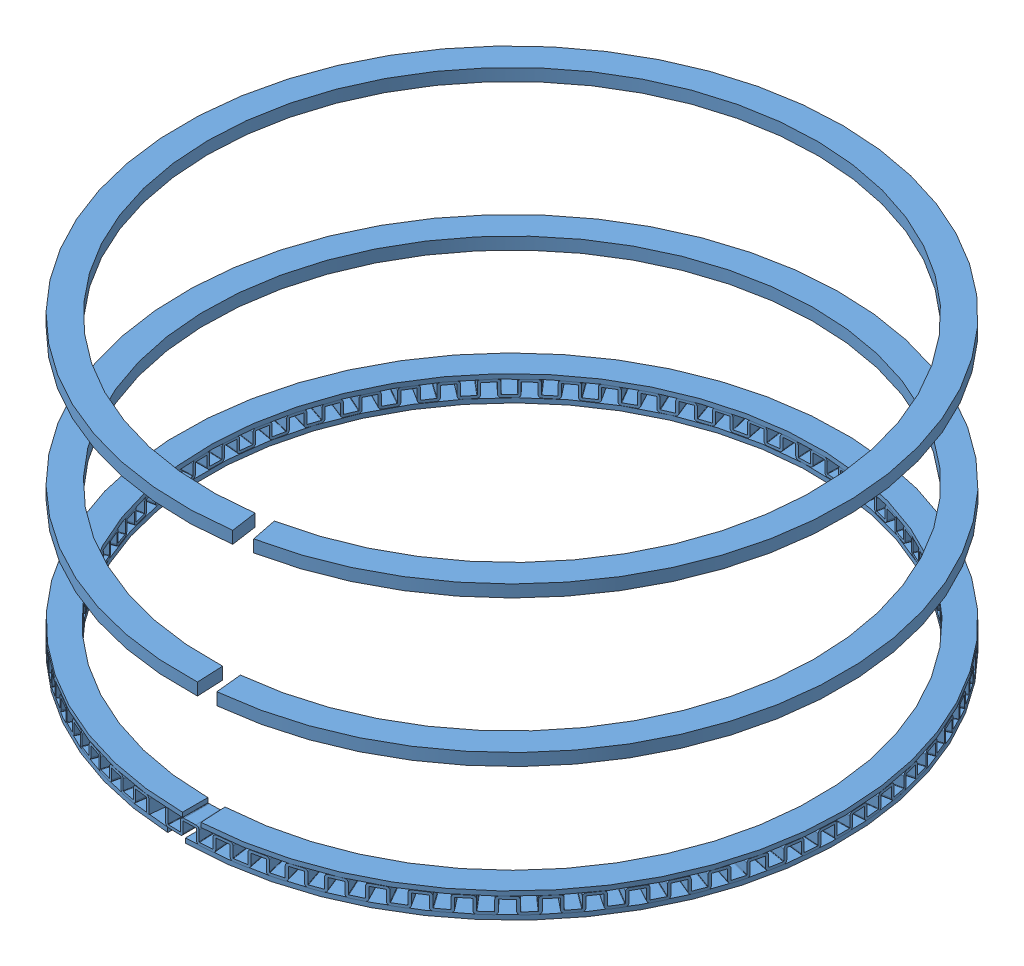
SolidWorks assembly 12140-45013, configuration PISTON RING SET (STD). Lengths in mm.
Overall size (73.59 28.72 73.59).
5 component instances, 1 part files, 9 mates.
Components (placement in the parent):
- 12111-45013-1: 12111-45013 [oliescchraapveer] x (1 0 0) z (0 -1 0) size (65 65 0.45)
- 12111-45013-2: 12111-45013 [oliescchraapveer] at (0 -2.05 0) x (0.998948 0 0.045854) z (0 -1 0) size (65 65 0.45)
- 12111-45013-3: 12111-45013 [olieschraapveer veer] at (0 -1.025 0) x (0.994205 0 0.107505) z (0 -1 0) size (65 65 1.63)
- 12111-45013-4: 12111-45013 [zuigerveer] at (0 25.8495 0) x (0.989813 0 -0.142376) z (0 -1 0) size (65 65 1.2)
- 12111-45013-5: 12111-45013 [zuigerveer] at (0 11.4496 0) x (0.999012 0 -0.044443) z (0 -1 0) size (65 65 1.2)
Mates (geometry in assembly coordinates):
- Coincident1: coincident anti-aligned: plane of 12111-45013-1 through (0 0 0) normal (0 -1 0)
- Coincident2: coincident aligned: plane of 12111-45013-1 through (0 0 0) normal (0 0 1)
- Coincident3: coincident aligned: plane of 12111-45013-1 through (0 0 0) normal (1 0 0)
- Coincident4: coincident anti-aligned: plane of 12111-45013-1 through (0 -0.225 32.5) normal (0 -1 0); plane of 12111-45013-3 through (0 -0.225 0) normal (0 1 0)
- Coincident5: coincident anti-aligned: plane of 12111-45013-2 through (-1.4902 -1.825 32.4658) normal (0 1 0); plane of 12111-45013-3 through (0 -1.825 0) normal (0 -1 0)
- Coincident9: coincident anti-aligned: line of 12111-45013-1 through (0.45 0 0.225) axis (0 0 -1); axis of 12111-45013-3 through (1.6 0 -1.825) axis (0 0 1)
- Coincident10: coincident anti-aligned: line of 12111-45013-2 through (0.45 0 -1.825) axis (0 0 -1); line of 12111-45013-3 through (1.6 0 -1.825) axis (0 0 1)
- Coincident11: coincident aligned: line of 12111-45013-4 through (1.2 0 26.4495) axis (0 0 -1); line of 12111-45013-5 through (1.2 0 12.0496) axis (0 0 -1)
- Coincident12: coincident anti-aligned: line of 12111-45013-3 through (1.6 0 -1.825) axis (0 0 1); line of 12111-45013-5 through (1.2 0 12.0496) axis (0 0 -1)
